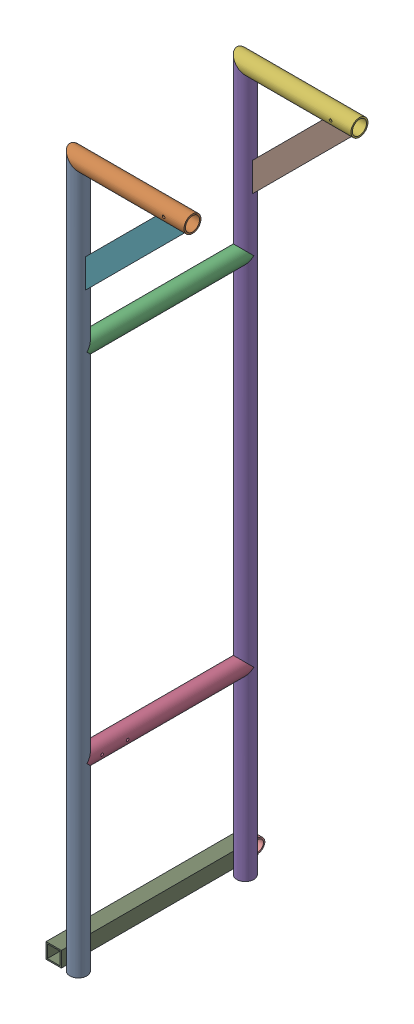
SolidWorks assembly GE-16046_LEFT_ASM, configuration Default. Lengths in mm.
Overall size (342.9 1771.65 505.65).
10 component instances, 7 part files, 0 mates.
Components (placement in the parent):
- GE-16046-01-1: GE-16046-01 [Default] at origin size (42.16 1771.65 42.16)
- GE-16046-02-1: GE-16046-02 [Default] at (131.318 864.743 0) x (0 -1 0) z (0 0 -1) size (42.16 304.8 42.16)
- GE-16046-03-1: GE-16046-03 [Default] at (0 457.2 -207.518) x (0 1 0) z (1 0 0) size (42.16 415.04 42.16)
- GE-16046-04-1: GE-16046-04 [Default] at (0 -428.625 -207.518) x (0 -1 0) z (1 0 0) size (42.16 415.04 42.16)
- GE-16046-01-2: GE-16046-01 [Default] at (0 0 -415.036) size (42.16 1771.65 42.16)
- GE-16046-02-2: GE-16046-02 [Default] at (131.318 864.743 -415.036) x (0 -1 0) z (0 0 -1) size (42.16 304.8 42.16)
- GE-16046-05-1: GE-16046-05 [Default] at (146.8056 753.8584 0) x (0.707107 0.707107 0) z (0 0 1) size (355.6 50.8 6.35)
- GE-16046-05-2: GE-16046-05 [Default] at (146.8056 753.8584 -415.036) x (0.707107 0.707107 0) z (0 0 1) size (355.6 50.8 6.35)
- GE-16046-06-1: GE-16046-06 [Default] at (-40.132 -860.425 -223.393) size (38.1 38.1 488.95)
- GE-16046-07-1: GE-16046-07 [Default] at (-40.132 -860.425 -467.868) x (0 1 0) z (0 0 1) size (33.4 38.1 33.4)
